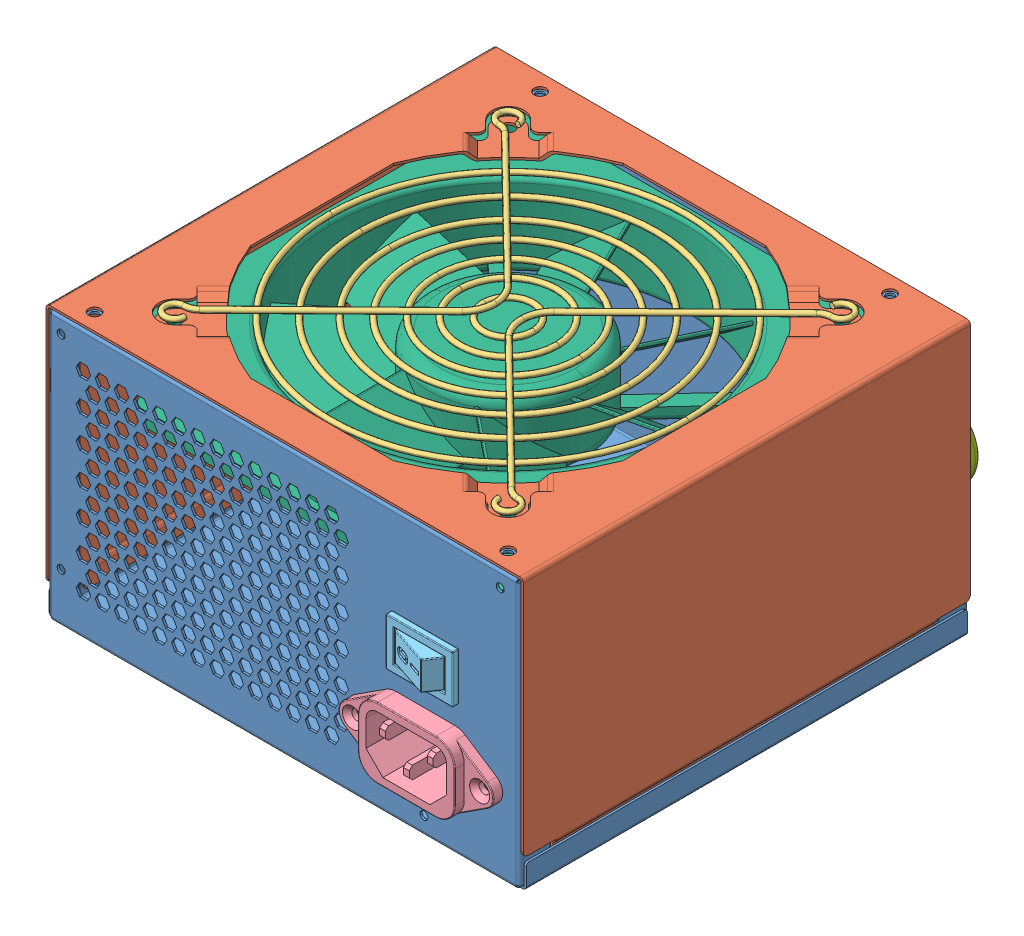
SolidWorks assembly ATX Power Supply v1.0, configuration Default. Lengths in mm.
Overall size (150 86.42 152).
7 component instances, 7 part files, 0 mates.
Components (placement in the parent):
- Box v1.0 - ATX Power Supply-1: Box v1.0 - ATX Power Supply [Default] at origin size (150 84.7 141.01)
- Cover v1.0 - ATX Power Supply-1: Cover v1.0 - ATX Power Supply [Default] at (0 2.9 0) size (150 82.63 140.5)
- Grelha Prot Vent 120-1: Grelha Prot Vent 120 [Default] at (0 85.55 0) x (-1 0 0) z (0 -1 0) size (115.85 114.72 3.29)
- IEC Plug-1: IEC Plug [Default] at (44.5 24 70.5) size (49.54 22 31)
- Switch on-off-1: Switch on-off [Default] at (36 54.5 62.5) x (0 -1 0) z (0 0 1) size (15 21 21.45)
- Ventax 119x119x26-1: Ventax 119x119x26 [Default] at (0 60.95 0) x (1 0 0) z (0 -1 0) size (124.36 129.72 26)
- Casq-1: Casq [Default] at (61.3 45 -58.5) x (1 0 0) z (0 1 0) size (24 17 24)
